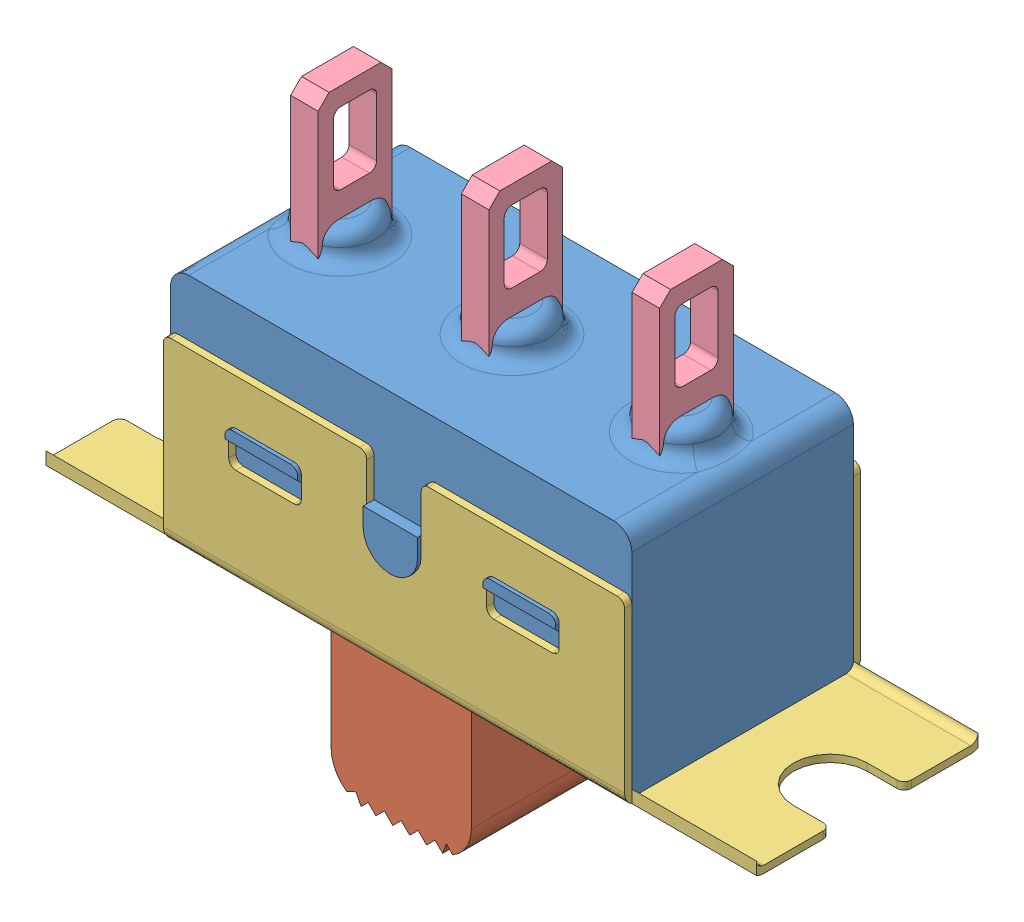
SolidWorks assembly 5MS1S102BM1QES, configuration Default. Lengths in mm.
Overall size (19.56 15.39 6.7).
4 component instances, 4 part files, 0 mates.
Components (placement in the parent):
- Corps-1: Corps [Default] at (-27.6 12.1333 0) size (12.7 7.15 6.7)
- Curseur-1: Curseur [Default] at (-27.6 13.1333 0) x (1 0 0) z (0 -1 0) size (6.1 3.86 6.08)
- Enveloppe-1: Enveloppe [Default] at (-27.6 12.1333 0) x (1 0 0) z (0 -1 0) size (19.56 6.5 5)
- Broches-1: Broches [Default] at (-27.6 18.4833 0) x (-1 0 0) z (0 1 0) size (10.16 2.03 3.96)
